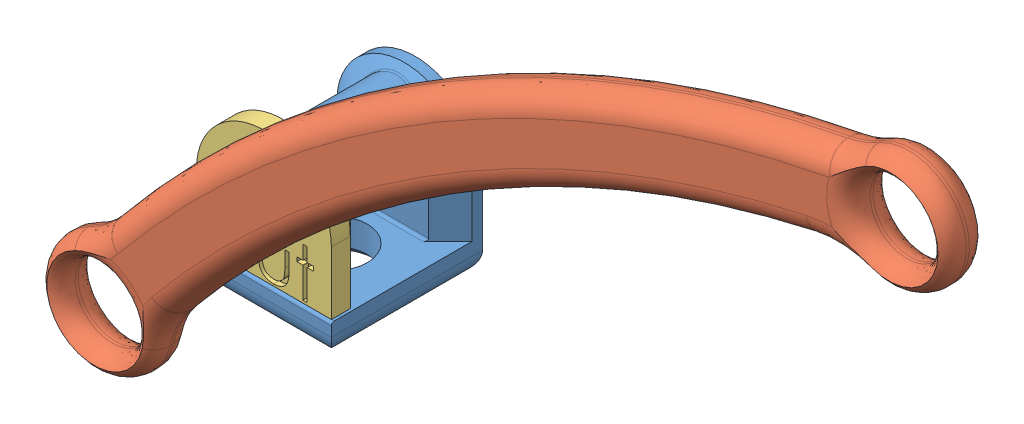
SolidWorks assembly Assem3, configuration Default. Lengths in mm.
Overall size (69.96 76.19 26.01).
3 component instances, 3 part files, 3 mates.
Components (placement in the parent):
- joint_swivel-1: joint_swivel [Default] at (-1.1505 2.6463 3.9731) size (10 11.55 12.2)
- leg_7cm-1: leg_7cm [Default] at (29.1931 33.1976 25.4034) x (-0.617172 -0.786751 0.011031) z (0.018268 -0.000312 0.999833) size (70.83 33.15 5.07)
- joint_swivel_cover-1: joint_swivel_cover [Default] at (8.8495 2.8463 15.1731) x (-1 0 0) z (0 0 -1) size (10 9.65 2.58)
Mates (geometry in assembly coordinates):
- Concentric2: concentric aligned: cylinder of joint_swivel-1 through (3.8495 8.8463 15.1731) axis (0 0 -1) radius 1.9; cylinder of joint_swivel_cover-1 through (3.8495 8.8463 15.7731) axis (0 0 -1) radius 2.1
- Parallel1: parallel anti-aligned: plane of joint_swivel-1 through (-1.1505 2.6463 15.1731) normal (0 1 0); plane of joint_swivel_cover-1 through (8.8495 2.8463 12.7731) normal (0 -1 0)
- Coincident2: coincident anti-aligned: plane of joint_swivel-1 through (3.8495 8.8463 15.1731) normal (0 0 -1); plane of joint_swivel_cover-1 through (3.8495 7.4971 15.1731) normal (0 0 1)
